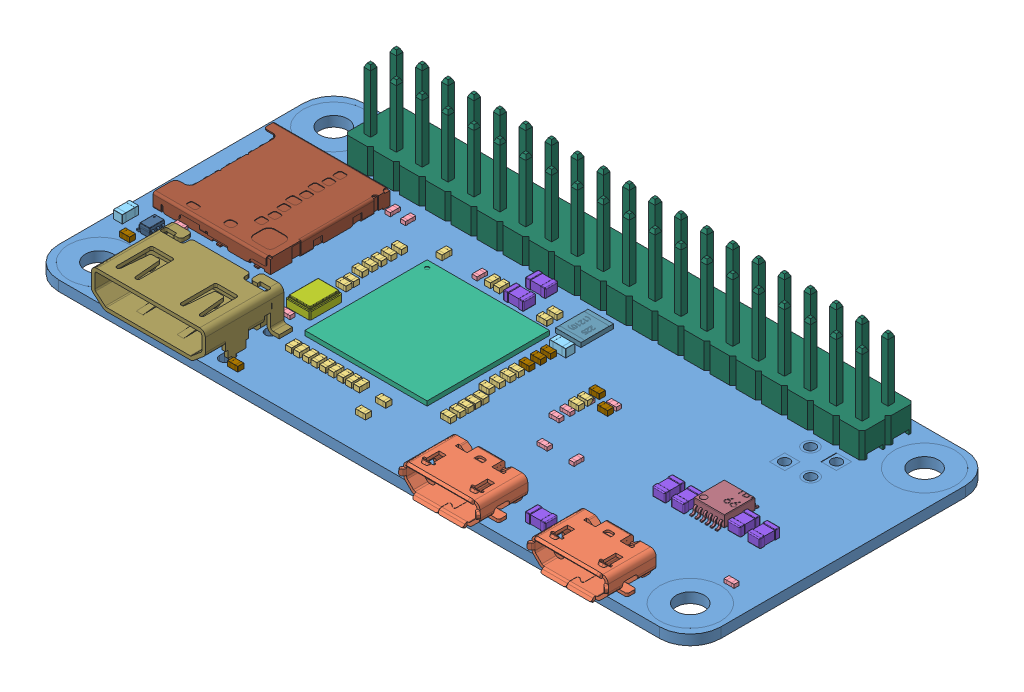
SolidWorks assembly RapberryPiZero, configuration Default. Lengths in mm.
Overall size (65 11.6 31.23).
74 component instances, 15 part files, 139 mates.
Components (placement in the parent):
- Raspberry_pizero_PCB-1: Raspberry_pizero_PCB [Default] at (-51.2564 20.0966 13.0542) size (65 1 30)
- Micro USB_input_female (short)-SMT-1: Micro USB_input_female (short)-SMT [Default] at (-42.3564 22.3216 26.5042) size (7.98 2.94 5.43)
- Micro USB_input_female (short)-SMT-2: Micro USB_input_female (short)-SMT [Default] at (-29.7564 22.3216 26.5042) size (7.98 2.94 5.43)
- 0204 - Capacitor-1: 0204 - Capacitor [Default] at (-66.1059 21.3466 14.3973) size (1 0.5 0.6)
- 0204 - Capacitor-2: 0204 - Capacitor [Default] at (-66.1059 21.3466 13.6661) size (1 0.5 0.6)
- 0204 - Capacitor-3: 0204 - Capacitor [Default] at (-66.4957 21.3466 8.5689) size (1 0.5 0.6)
- 0204 - Capacitor-4: 0204 - Capacitor [Default] at (-66.4957 21.3466 9.5922) size (1 0.5 0.6)
- 0204 - Capacitor-5: 0204 - Capacitor [Default] at (-66.4957 21.3466 10.5547) size (1 0.5 0.6)
- 0204 - Capacitor-6: 0204 - Capacitor [Default] at (-66.4957 21.3466 11.4563) size (1 0.5 0.6)
- 0204 - Capacitor-7: 0204 - Capacitor [Default] at (-66.4957 21.3466 12.4125) size (1 0.5 0.6)
- 0204 - Capacitor-8: 0204 - Capacitor [Default] at (-54.2619 21.3466 22.342) size (1 0.5 0.6)
- 0204 - Capacitor-9: 0204 - Capacitor [Default] at (-54.2619 21.3466 24.3333) size (1 0.5 0.6)
- 0204 - Capacitor-10: 0204 - Capacitor [Default] at (-63.0188 21.3466 22.4185) x (0 0 1) z (-1 0 0) size (1 0.5 0.6)
- 0204 - Capacitor-11: 0204 - Capacitor [Default] at (-62.8505 21.3466 22.4185) x (0 0 -1) z (1 0 0) size (1 0.5 0.6)
- 0204 - Capacitor-12: 0204 - Capacitor [Default] at (-61.9536 21.3466 22.4185) x (0 0 -1) z (1 0 0) size (1 0.5 0.6)
- 0204 - Capacitor-13: 0204 - Capacitor [Default] at (-60.535 21.3466 22.4217) x (0 0 1) z (-1 0 0) size (1 0.5 0.6)
- 0204 - Capacitor-14: 0204 - Capacitor [Default] at (-60.2749 21.3466 22.4217) x (0 0 -1) z (1 0 0) size (1 0.5 0.6)
- 0204 - Capacitor-15: 0204 - Capacitor [Default] at (-59.4762 21.3466 22.4217) x (0 0 -1) z (1 0 0) size (1 0.5 0.6)
- 0204 - Capacitor-16: 0204 - Capacitor [Default] at (-58.5578 21.3466 22.4217) x (0 0 -1) z (1 0 0) size (1 0.5 0.6)
- 0204 - Capacitor-17: 0204 - Capacitor [Default] at (-57.7282 21.3466 22.4217) x (0 0 -1) z (1 0 0) size (1 0.5 0.6)
- 0204 - Capacitor-18: 0204 - Capacitor [Default] at (-49.7633 21.3466 17.2973) size (1 0.5 0.6)
- 0204 - Capacitor-19: 0204 - Capacitor [Default] at (-49.7656 21.3466 20.4911) size (1 0.5 0.6)
- 0204 - Capacitor-20: 0204 - Capacitor [Default] at (-49.7656 21.3466 19.5641) size (1 0.5 0.6)
- 0204 - Capacitor-21: 0204 - Capacitor [Default] at (-49.7656 21.3466 18.764) size (1 0.5 0.6)
- 0204 - Capacitor-22: 0204 - Capacitor [Default] at (-49.7656 21.3466 18.0575) size (1 0.5 0.6)
- 0204 - Capacitor-23: 0204 - Capacitor [Default] at (-50.3207 21.3466 16.1412) size (1 0.5 0.6)
- 0204 - Capacitor-24: 0204 - Capacitor [Default] at (-50.3207 21.3466 15.1225) size (1 0.5 0.6)
- 0204 - Capacitor-25: 0204 - Capacitor [Default] at (-50.3207 21.3466 14.0903) size (1 0.5 0.6)
- 0204 - Capacitor-26: 0204 - Capacitor [Default] at (-50.3207 21.3466 13.2438) size (1 0.5 0.6)
- 0204 - Capacitor-27: 0204 - Capacitor [Default] at (-44.527 21.3466 13.1418) size (1 0.5 0.6)
- 0204 - Capacitor-28: 0204 - Capacitor [Default] at (-44.527 21.3466 12.278) size (1 0.5 0.6)
- 0204 - Capacitor-29: 0204 - Capacitor [Default] at (-53.3159 21.3466 7.4799) size (1 0.5 0.6)
- 0204 - Capacitor-30: 0204 - Capacitor [Default] at (-59.3985 21.3466 7.1313) x (0 0 -1) z (1 0 0) size (1 0.5 0.6)
- 0204 - Capacitor-31: 0204 - Capacitor [Default] at (-57.9118 21.3466 7.1313) x (0 0 1) z (-1 0 0) size (1 0.5 0.6)
- 0204 - Capacitor-32: 0204 - Capacitor [Default] at (-63.5406 21.3466 7.1313) x (0 0 1) z (-1 0 0) size (1 0.5 0.6)
- 0204- Resistor-15: 0204- Resistor [Default] at (-44.5223 21.4522 15.4193) x (-1 0 0) z (0 -1 0) size (0.99 0.51 0.36)
- 0204- Resistor-14: 0204- Resistor [Default] at (-44.5223 21.4522 14.3417) x (-1 0 0) z (0 -1 0) size (0.99 0.51 0.36)
- 0204- Resistor-13: 0204- Resistor [Default] at (-44.5223 21.4522 12.4047) x (-1 0 0) z (0 -1 0) size (0.99 0.51 0.36)
- 0204- Resistor-4: 0204- Resistor [Default] at (-42.6936 21.4522 18.4076) x (-1 0 0) z (0 -1 0) size (0.99 0.51 0.36)
- 0204- Resistor-5: 0204- Resistor [Default] at (-39.831 21.4522 18.1462) x (0 0 1) z (0 -1 0) size (0.99 0.51 0.36)
- 0204- Resistor-7: 0204- Resistor [Default] at (-66.5004 21.4522 19.8533) x (-1 0 0) z (0 -1 0) size (0.99 0.51 0.36)
- 0204- Resistor-9: 0204- Resistor [Default] at (-79.148 21.4522 17.7279) x (-1 0 0) z (0 -1 0) size (0.99 0.51 0.36)
- 0204- Resistor-10: 0204- Resistor [Default] at (-60.3595 21.4522 7.1266) x (0 0 -1) z (0 -1 0) size (0.99 0.51 0.36)
- 0204- Resistor-11: 0204- Resistor [Default] at (-42.6893 21.4522 11.6167) x (-1 0 0) z (0 -1 0) size (0.99 0.51 0.36)
- 0204- Resistor-12: 0204- Resistor [Default] at (-21.8613 21.4522 20.9026) x (-1 0 0) z (0 -1 0) size (0.99 0.51 0.36)
- CAP-0306-1: CAP-0306 [Default] at (-50.0081 21.4966 8.9291) size (1.6 0.8 0.9)
- CAP-0306-2: CAP-0306 [Default] at (-82.3562 21.4966 19.4035) x (0 0 1) z (-1 0 0) size (1.6 0.8 0.9)
- Raspberry_pizero_BCM2835 with VC4-2: Raspberry_pizero_BCM2835 with VC4 [Default] at (-57.9267 21.5466 14.7194) x (1 0 0) z (0 0 -1) size (12 0.65 12)
- Crystal 3.4x2.4mm-1: Crystal 3.4x2.4mm [Default] at (-66.1441 21.0966 17.5946) x (0 0 1) z (-1 0 0) size (3.2 1 2.4)
- 0204- Resistor-16: 0204- Resistor [Default] at (-68.5745 21.4522 5.9384) x (0 0 1) z (0 -1 0) size (0.99 0.51 0.36)
- 0204- Resistor-17: 0204- Resistor [Default] at (-70.0781 21.4522 5.9384) x (0 0 1) z (0 -1 0) size (0.99 0.51 0.36)
- 0805- Capacitor-1: 0805- Capacitor [Default] at (-56.2106 21.9966 5.1919) x (1 0 0) z (0 -1 0) size (2 1.25 0.9)
- 0805- Capacitor-2: 0805- Capacitor [Default] at (-56.2106 21.9966 7.3589) x (1 0 0) z (0 -1 0) size (2 1.25 0.9)
- 0805- Capacitor-3: 0805- Capacitor [Default] at (-36.3007 21.9966 25.1368) x (1 0 0) z (0 -1 0) size (2 1.25 0.9)
- 0805- Capacitor-4: 0805- Capacitor [Default] at (-32.5762 21.9966 16.3326) x (0 0 1) z (0 -1 0) size (2 1.25 0.9)
- 0805- Capacitor-5: 0805- Capacitor [Default] at (-30.7451 21.9966 16.3326) x (0 0 -1) z (0 -1 0) size (2 1.25 0.9)
- 0805- Capacitor-6: 0805- Capacitor [Default] at (-26.001 21.9966 15.5523) x (0 0 -1) z (0 -1 0) size (2 1.25 0.9)
- 0805- Capacitor-7: 0805- Capacitor [Default] at (-24.0466 21.9966 15.5523) x (0 0 -1) z (0 -1 0) size (2 1.25 0.9)
- 0204 - Capacitor-33: 0204 - Capacitor [Default] at (-56.3601 21.3466 22.4168) x (0 0 1) z (-1 0 0) size (1 0.5 0.6)
- 0204 - Capacitor Brown-35: 0204 - Capacitor Brown [Default] at (-64.6013 21.3466 26.5277) size (1 0.5 0.6)
- 0204 - Capacitor Brown-36: 0204 - Capacitor Brown [Default] at (-50.3207 21.3466 12.214) size (1 0.5 0.6)
- 0204 - Capacitor Brown-37: 0204 - Capacitor Brown [Default] at (-50.3207 21.3466 11.0963) size (1 0.5 0.6)
- 0204 - Capacitor Brown-38: 0204 - Capacitor Brown [Default] at (-50.3207 21.3466 10.1084) size (1 0.5 0.6)
- 0204 - Capacitor Brown-39: 0204 - Capacitor Brown [Default] at (-44.527 21.3466 11.1151) size (1 0.5 0.6)
- 0204 - Capacitor Brown-40: 0204 - Capacitor Brown [Default] at (-42.694 21.3466 12.1364) size (1 0.5 0.6)
- 0204 - Capacitor Brown-41: 0204 - Capacitor Brown [Default] at (-80.9029 21.3466 20.8434) size (1 0.5 0.6)
- 0204- Resistor-21: 0204- Resistor [Default] at (-79.0538 21.4522 20.9432) x (1 0 0) z (0 -1 0) size (0.99 0.51 0.36)
- 6-Pin SOT-1: 6-Pin SOT [Default] at (-80.2098 21.0966 19.4296) x (0 0 1) z (0 1 0) size (1.5 1.84 0.95)
- micro sd molex-1: micro sd molex [Default] at (-74.7768 21.6766 -33.0961) x (0 0 1) z (0 1 0) size (11.95 11.4 1.45)
- hdmi type C-1: hdmi type C [Default] at (-71.3564 22.9466 28.6542) size (12.9 4.05 7.7)
- Voltage Regulator 3x3mm 12-Pin-1: Voltage Regulator 3x3mm 12-Pin [Default] at (-26.5859 21.0966 14.3315) x (1 0 0) z (0 1 0) size (3 4.1 1.2)
- 1210 inductor-1: 1210 inductor [Default] at (-50.6117 20.9774 6.5916) x (0 0 1) z (0 1 0) size (3.26 2.86 0.75)
- 0204 - Capacitor-34: 0204 - Capacitor [Default] at (-53.3159 21.3466 6.4804) size (1 0.5 0.6)
- raspberry_pi_B+_(bar_180_2x20)-1: raspberry_pi_B+_(bar_180_2x20) [Default] at (-75.3864 23.5966 0.2742) x (0 0 -1) z (-1 0 0) size (5.08 11.6 50.8)
Mates (geometry in assembly coordinates):
- Coincident1: coincident anti-aligned: plane of Raspberry_pizero_PCB-1 through (-80.7564 21.0966 1.0542) normal (0 1 0); plane of Micro USB_input_female (short)-SMT-1 through (-46.4124 21.0966 24.8966) normal (0 -1 0)
- Coincident2: coincident anti-aligned: plane of Raspberry_pizero_PCB-1 through (-80.7564 21.0966 1.0542) normal (0 1 0); plane of Micro USB_input_female (short)-SMT-2 through (-33.8124 21.0966 24.8966) normal (0 -1 0)
- Coincident3: coincident aligned: plane of 0204 - Capacitor-13 through (-60.837 21.5916 22.4217) normal (0 1 0); plane of 0204 - Capacitor-14 through (-59.9729 21.5916 22.4217) normal (0 1 0)
- Coincident4: coincident aligned: plane of 0204 - Capacitor-14 through (-59.9729 21.5916 22.4217) normal (0 1 0); plane of 0204 - Capacitor-15 through (-59.1742 21.5916 22.4217) normal (0 1 0)
- Coincident5: coincident aligned: plane of 0204 - Capacitor-15 through (-59.1742 21.5916 22.4217) normal (0 1 0); plane of 0204 - Capacitor-16 through (-58.2558 21.5916 22.4217) normal (0 1 0)
- Coincident6: coincident aligned: plane of 0204 - Capacitor-16 through (-58.2558 21.5916 22.4217) normal (0 1 0); plane of 0204 - Capacitor-17 through (-57.4262 21.5916 22.4217) normal (0 1 0)
- Coincident7: coincident aligned: plane of 0204 - Capacitor-17 through (-57.4262 21.5916 22.4217) normal (0 1 0); plane of 0204 - Capacitor-18 through (-49.7633 21.5916 17.5993) normal (0 1 0)
- Coincident8: coincident aligned: plane of 0204 - Capacitor-18 through (-49.7633 21.5916 17.5993) normal (0 1 0); plane of 0204 - Capacitor-19 through (-49.7656 21.5916 20.7931) normal (0 1 0)
- Coincident9: coincident aligned: plane of 0204 - Capacitor-19 through (-49.7656 21.5916 20.7931) normal (0 1 0); plane of 0204 - Capacitor-20 through (-49.7656 21.5916 19.8661) normal (0 1 0)
- Coincident10: coincident aligned: plane of 0204 - Capacitor-20 through (-49.7656 21.5916 19.8661) normal (0 1 0); plane of 0204 - Capacitor-21 through (-49.7656 21.5916 19.066) normal (0 1 0)
- Coincident11: coincident aligned: plane of 0204 - Capacitor-21 through (-49.7656 21.5916 19.066) normal (0 1 0); plane of 0204 - Capacitor-22 through (-49.7656 21.5916 18.3595) normal (0 1 0)
- Coincident12: coincident aligned: plane of 0204 - Capacitor-22 through (-49.7656 21.5916 18.3595) normal (0 1 0); plane of 0204 - Capacitor-23 through (-50.3207 21.5916 16.4432) normal (0 1 0)
- Coincident13: coincident aligned: plane of 0204 - Capacitor-23 through (-50.3207 21.5916 16.4432) normal (0 1 0); plane of 0204 - Capacitor-24 through (-50.3207 21.5916 15.4245) normal (0 1 0)
- Coincident14: coincident aligned: plane of 0204 - Capacitor-24 through (-50.3207 21.5916 15.4245) normal (0 1 0); plane of 0204 - Capacitor-25 through (-50.3207 21.5916 14.3923) normal (0 1 0)
- Coincident15: coincident aligned: plane of 0204 - Capacitor-25 through (-50.3207 21.5916 14.3923) normal (0 1 0); plane of 0204 - Capacitor-26 through (-50.3207 21.5916 13.5458) normal (0 1 0)
- Coincident16: coincident aligned: plane of 0204 - Capacitor-26 through (-50.3207 21.5916 13.5458) normal (0 1 0); plane of 0204 - Capacitor-27 through (-44.527 21.5916 13.4438) normal (0 1 0)
- Coincident17: coincident aligned: plane of 0204 - Capacitor-27 through (-44.527 21.5916 13.4438) normal (0 1 0); plane of 0204 - Capacitor-28 through (-44.527 21.5916 12.58) normal (0 1 0)
- Coincident18: coincident aligned: plane of 0204 - Capacitor-28 through (-44.527 21.5916 12.58) normal (0 1 0); plane of 0204 - Capacitor-29 through (-53.3159 21.5916 7.7819) normal (0 1 0)
- Coincident19: coincident aligned: plane of 0204 - Capacitor-29 through (-53.3159 21.5916 7.7819) normal (0 1 0); plane of 0204 - Capacitor-31 through (-58.2138 21.5916 7.1313) normal (0 1 0)
- Coincident20: coincident aligned: plane of 0204 - Capacitor-30 through (-59.0965 21.5916 7.1313) normal (0 1 0); plane of 0204 - Capacitor-31 through (-58.2138 21.5916 7.1313) normal (0 1 0)
- Coincident21: coincident aligned: plane of 0204 - Capacitor-30 through (-59.0965 21.5916 7.1313) normal (0 1 0); plane of 0204 - Capacitor-32 through (-63.8426 21.5916 7.1313) normal (0 1 0)
- Coincident22: coincident aligned: plane of 0204 - Capacitor-1 through (-66.1059 21.5916 14.6993) normal (0 1 0); plane of 0204 - Capacitor-32 through (-63.8426 21.5916 7.1313) normal (0 1 0)
- Coincident23: coincident aligned: plane of 0204 - Capacitor-1 through (-66.1059 21.5916 14.6993) normal (0 1 0); plane of 0204 - Capacitor-2 through (-66.1059 21.5916 13.9681) normal (0 1 0)
- Coincident24: coincident aligned: plane of 0204 - Capacitor-2 through (-66.1059 21.5916 13.9681) normal (0 1 0); plane of 0204 - Capacitor-3 through (-66.4957 21.5916 8.8709) normal (0 1 0)
- Coincident25: coincident aligned: plane of 0204 - Capacitor-3 through (-66.4957 21.5916 8.8709) normal (0 1 0); plane of 0204 - Capacitor-4 through (-66.4957 21.5916 9.8942) normal (0 1 0)
- Coincident26: coincident aligned: plane of 0204 - Capacitor-4 through (-66.4957 21.5916 9.8942) normal (0 1 0); plane of 0204 - Capacitor-5 through (-66.4957 21.5916 10.8567) normal (0 1 0)
- Coincident27: coincident aligned: plane of 0204 - Capacitor-5 through (-66.4957 21.5916 10.8567) normal (0 1 0); plane of 0204 - Capacitor-6 through (-66.4957 21.5916 11.7583) normal (0 1 0)
- Coincident28: coincident aligned: plane of 0204 - Capacitor-6 through (-66.4957 21.5916 11.7583) normal (0 1 0); plane of 0204 - Capacitor-7 through (-66.4957 21.5916 12.7145) normal (0 1 0)
- Coincident29: coincident aligned: plane of 0204 - Capacitor-7 through (-66.4957 21.5916 12.7145) normal (0 1 0); plane of 0204 - Capacitor-8 through (-54.2619 21.5916 22.644) normal (0 1 0)
- Coincident31: coincident aligned: plane of 0204 - Capacitor-9 through (-54.2619 21.5916 24.6353) normal (0 1 0); plane of 0204 - Capacitor-10 through (-63.3208 21.5916 22.4185) normal (0 1 0)
- Coincident30: coincident aligned: plane of 0204 - Capacitor-8 through (-54.2619 21.5916 22.644) normal (0 1 0); plane of 0204 - Capacitor-9 through (-54.2619 21.5916 24.6353) normal (0 1 0)
- Coincident32: coincident aligned: plane of 0204 - Capacitor-10 through (-63.3208 21.5916 22.4185) normal (0 1 0); plane of 0204 - Capacitor-11 through (-62.5485 21.5916 22.4185) normal (0 1 0)
- Coincident33: coincident aligned: plane of 0204 - Capacitor-11 through (-62.5485 21.5916 22.4185) normal (0 1 0); plane of 0204 - Capacitor-12 through (-61.6516 21.5916 22.4185) normal (0 1 0)
- Coincident34: coincident anti-aligned: plane of Raspberry_pizero_PCB-1 through (-80.7564 21.0966 1.0542) normal (0 1 0); plane of 0204 - Capacitor-9 through (-54.6369 21.0966 24.6333) normal (0 -1 0)
- Coincident35: coincident aligned: plane of 0204 - Capacitor-25 through (-50.8207 21.0966 14.3903) normal (-1 0 0); plane of 0204 - Capacitor-26 through (-50.8207 21.0966 13.5438) normal (-1 0 0)
- Coincident36: coincident aligned: plane of 0204 - Capacitor-24 through (-50.8207 21.0966 15.4225) normal (-1 0 0); plane of 0204 - Capacitor-25 through (-50.8207 21.0966 14.3903) normal (-1 0 0)
- Coincident37: coincident aligned: plane of 0204 - Capacitor-23 through (-50.8207 21.0966 16.4412) normal (-1 0 0); plane of 0204 - Capacitor-24 through (-50.8207 21.0966 15.4225) normal (-1 0 0)
- Coincident38: coincident aligned: plane of 0204 - Capacitor-27 through (-45.027 21.0966 13.4418) normal (-1 0 0); plane of 0204 - Capacitor-28 through (-45.027 21.0966 12.578) normal (-1 0 0)
- Parallel1: parallel anti-aligned: plane of Raspberry_pizero_PCB-1 through (-80.7564 21.0966 -1.9458) normal (0 0 -1); plane of 0204 - Capacitor-30 through (-59.0985 21.0966 7.6313) normal (0 0 1)
- Coincident39: coincident aligned: plane of 0204 - Capacitor-30 through (-59.0985 21.0966 6.6313) normal (0 0 -1); plane of 0204 - Capacitor-31 through (-58.2118 21.0966 6.6313) normal (0 0 -1)
- Coincident40: coincident aligned: plane of 0204 - Capacitor-30 through (-59.0985 21.0966 6.6313) normal (0 0 -1); plane of 0204 - Capacitor-32 through (-63.8406 21.0966 6.6313) normal (0 0 -1)
- Coincident41: coincident aligned: plane of 0204 - Capacitor-1 through (-66.6059 21.0966 14.6973) normal (-1 0 0); plane of 0204 - Capacitor-2 through (-66.6059 21.0966 13.9661) normal (-1 0 0)
- Coincident42: coincident aligned: plane of 0204 - Capacitor-3 through (-66.9957 21.0966 8.8689) normal (-1 0 0); plane of 0204 - Capacitor-4 through (-66.9957 21.0966 9.8922) normal (-1 0 0)
- Coincident43: coincident aligned: plane of 0204 - Capacitor-4 through (-66.9957 21.0966 9.8922) normal (-1 0 0); plane of 0204 - Capacitor-5 through (-66.9957 21.0966 10.8547) normal (-1 0 0)
- Coincident44: coincident aligned: plane of 0204 - Capacitor-5 through (-66.9957 21.0966 10.8547) normal (-1 0 0); plane of 0204 - Capacitor-6 through (-66.9957 21.0966 11.7563) normal (-1 0 0)
- Coincident45: coincident aligned: plane of 0204 - Capacitor-6 through (-66.9957 21.0966 11.7563) normal (-1 0 0); plane of 0204 - Capacitor-7 through (-66.9957 21.0966 12.7125) normal (-1 0 0)
- Coincident46: coincident aligned: plane of 0204 - Capacitor-8 through (-54.7619 21.0966 22.642) normal (-1 0 0); plane of 0204 - Capacitor-9 through (-54.7619 21.0966 24.6333) normal (-1 0 0)
- Parallel2: parallel anti-aligned: plane of Raspberry_pizero_PCB-1 through (-80.7564 21.0966 28.0542) normal (0 0 1); plane of 0204 - Capacitor-10 through (-63.3188 21.0966 21.9185) normal (0 0 -1)
- Coincident48: coincident aligned: plane of 0204 - Capacitor-10 through (-63.3188 21.0966 22.9185) normal (0 0 1); plane of 0204 - Capacitor-11 through (-62.5505 21.0966 22.9185) normal (0 0 1)
- Coincident49: coincident aligned: plane of 0204 - Capacitor-11 through (-62.5505 21.0966 22.9185) normal (0 0 1); plane of 0204 - Capacitor-12 through (-61.6536 21.0966 22.9185) normal (0 0 1)
- Parallel3: parallel anti-aligned: plane of Raspberry_pizero_PCB-1 through (-80.7564 21.0966 28.0542) normal (0 0 1); plane of 0204 - Capacitor-13 through (-60.835 21.0966 21.9217) normal (0 0 -1)
- Coincident51: coincident aligned: plane of 0204 - Capacitor-13 through (-60.835 21.0966 22.9217) normal (0 0 1); plane of 0204 - Capacitor-14 through (-59.9749 21.0966 22.9217) normal (0 0 1)
- Coincident52: coincident aligned: plane of 0204 - Capacitor-14 through (-59.9749 21.0966 22.9217) normal (0 0 1); plane of 0204 - Capacitor-15 through (-59.1762 21.0966 22.9217) normal (0 0 1)
- Coincident53: coincident aligned: plane of 0204 - Capacitor-15 through (-59.1762 21.0966 22.9217) normal (0 0 1); plane of 0204 - Capacitor-16 through (-58.2578 21.0966 22.9217) normal (0 0 1)
- Coincident54: coincident aligned: plane of 0204 - Capacitor-16 through (-58.2578 21.0966 22.9217) normal (0 0 1); plane of 0204 - Capacitor-17 through (-57.4282 21.0966 22.9217) normal (0 0 1)
- Parallel7: parallel anti-aligned: plane of Raspberry_pizero_PCB-1 through (-80.7564 21.0966 28.0542) normal (0 0 1); plane of CAP-0306-2 through (-82.8062 21.0966 18.6035) normal (0 0 -1)
- Parallel8: parallel aligned: plane of Raspberry_pizero_PCB-1 through (-18.7564 21.0966 25.0542) normal (1 0 0); plane of CAP-0306-1 through (-49.2081 21.0966 9.3791) normal (1 0 0)
- Coincident77: coincident aligned: plane of 0204 - Capacitor-21 through (-50.2656 21.0966 19.064) normal (-1 0 0); plane of 0204 - Capacitor-22 through (-50.2656 21.0966 18.3575) normal (-1 0 0)
- Coincident78: coincident aligned: plane of 0204 - Capacitor-20 through (-50.2656 21.0966 19.8641) normal (-1 0 0); plane of 0204 - Capacitor-21 through (-50.2656 21.0966 19.064) normal (-1 0 0)
- Coincident79: coincident aligned: plane of 0204 - Capacitor-19 through (-50.2656 21.0966 20.7911) normal (-1 0 0); plane of 0204 - Capacitor-20 through (-50.2656 21.0966 19.8641) normal (-1 0 0)
- Coincident80: coincident aligned: plane of Micro USB_input_female (short)-SMT-1 through (-39.2364 21.3596 23.8542) normal (0 0 -1); plane of Micro USB_input_female (short)-SMT-2 through (-26.6364 21.3596 23.8542) normal (0 0 -1)
- Distance1: distance = 41.4 mm: point of Micro USB_input_female (short)-SMT-1; plane of Raspberry_pizero_PCB-1 through (-83.7564 21.0966 25.0542) normal (-1 0 0)
- Distance3: distance = 0.8 mm aligned: plane of Micro USB_input_female (short)-SMT-1 through (-46.2564 21.0476 28.8542) normal (0 0 1); plane of Raspberry_pizero_PCB-1 through (-80.7564 21.0966 28.0542) normal (0 0 1)
- Distance4: distance = 54 mm: unknown of Micro USB_input_female (short)-SMT-2; plane of Raspberry_pizero_PCB-1 through (-83.7564 21.0966 25.0542) normal (-1 0 0)
- Coincident86: coincident anti-aligned: plane of Raspberry_pizero_PCB-1 through (-80.7564 21.0966 1.0542) normal (0 1 0); plane of Raspberry_pizero_BCM2835 with VC4-2 through (-57.9267 21.0966 14.7194) normal (0 -1 0)
- Parallel10: parallel anti-aligned: plane of Raspberry_pizero_BCM2835 with VC4-2 through (-63.9267 21.0966 8.7194) normal (0 0 -1); plane of Raspberry_pizero_PCB-1 through (-80.7564 21.0966 28.0542) normal (0 0 1)
- Coincident88: coincident anti-aligned: plane of Raspberry_pizero_PCB-1 through (-80.7564 21.0966 1.0542) normal (0 1 0); plane of CAP-0306-1 through (-49.3831 21.0966 9.3791) normal (0 -1 0)
- Parallel11: parallel aligned: plane of Raspberry_pizero_PCB-1 through (-80.7564 21.0966 28.0542) normal (0 0 1); plane of 0204 - Capacitor-7 through (-66.4957 21.1016 13.0115) normal (0 0 1)
- Coincident94: coincident aligned: plane of 0204 - Capacitor-30 through (-59.0985 21.0966 6.6313) normal (0 0 -1); plane of 0204- Resistor-10 through (-60.1055 21.0966 6.6313) normal (0 0 -1)
- Coincident95: coincident anti-aligned: plane of Raspberry_pizero_PCB-1 through (-80.7564 21.0966 1.0542) normal (0 1 0); plane of 0204- Resistor-10 through (-60.1055 21.0966 6.8345) normal (0 -1 0)
- Coincident96: coincident aligned: plane of 0204- Resistor-14 through (-44.8144 21.0966 14.0877) normal (0 -1 0); plane of 0204- Resistor-13 through (-44.8144 21.0966 12.1507) normal (0 -1 0)
- Coincident97: coincident aligned: plane of 0204- Resistor-15 through (-44.8144 21.0966 15.1653) normal (0 -1 0); plane of 0204- Resistor-14 through (-44.8144 21.0966 14.0877) normal (0 -1 0)
- Coincident98: coincident aligned: plane of 0204- Resistor-15 through (-44.8144 21.0966 15.1653) normal (0 -1 0); plane of 0204- Resistor-4 through (-42.9857 21.0966 18.1536) normal (0 -1 0)
- Coincident99: coincident anti-aligned: plane of Raspberry_pizero_PCB-1 through (-80.7564 21.0966 1.0542) normal (0 1 0); plane of 0204- Resistor-15 through (-44.8144 21.0966 15.1653) normal (0 -1 0)
- Coincident101: coincident aligned: plane of 0204- Resistor-5 through (-40.085 21.0966 18.4383) normal (0 -1 0); plane of 0204- Resistor-11 through (-42.3972 21.0966 11.3627) normal (0 -1 0)
- Coincident102: coincident aligned: plane of 0204- Resistor-11 through (-42.3972 21.0966 11.3627) normal (0 -1 0); plane of 0204- Resistor-12 through (-21.5692 21.0966 20.6486) normal (0 -1 0)
- Coincident103: coincident anti-aligned: plane of Raspberry_pizero_PCB-1 through (-80.7564 21.0966 1.0542) normal (0 1 0); plane of Crystal 3.4x2.4mm-1 through (-66.1441 21.0966 17.5946) normal (0 -1 0)
- Parallel12: parallel aligned: plane of Crystal 3.4x2.4mm-1 through (-67.3441 21.7966 15.9946) normal (-1 0 0); plane of Raspberry_pizero_BCM2835 with VC4-2 through (-63.9267 21.0966 8.7194) normal (-1 0 0)
- Coincident104: coincident anti-aligned: plane of Raspberry_pizero_PCB-1 through (-80.7564 21.0966 1.0542) normal (0 1 0); plane of 0204- Resistor-9 through (-78.8559 21.0966 17.4739) normal (0 -1 0)
- Parallel13: parallel aligned: plane of Raspberry_pizero_PCB-1 through (-80.7564 21.0966 28.0542) normal (0 0 1); plane of 0204- Resistor-9 through (-78.2985 21.4532 17.9829) normal (0 0 1)
- Coincident105: coincident anti-aligned: plane of Raspberry_pizero_PCB-1 through (-80.7564 21.0966 1.0542) normal (0 1 0); plane of CAP-0306-2 through (-82.8062 21.0966 20.0285) normal (0 -1 0)
- Coincident106: coincident aligned: plane of 0204 - Capacitor-28 through (-44.027 21.0966 12.578) normal (1 0 0); plane of 0204- Resistor-13 through (-44.027 21.0966 12.1507) normal (1 0 0)
- Coincident107: coincident aligned: plane of 0204 - Capacitor-27 through (-44.027 21.0966 13.4418) normal (1 0 0); plane of 0204- Resistor-14 through (-44.027 21.0966 14.0877) normal (1 0 0)
- Parallel14: parallel aligned: plane of Raspberry_pizero_PCB-1 through (-80.7564 21.0966 28.0542) normal (0 0 1); plane of 0204- Resistor-14 through (-43.6728 21.4532 14.5967) normal (0 0 1)
- Coincident110: coincident aligned: plane of 0204- Resistor-15 through (-44.027 21.0966 15.1653) normal (1 0 0); plane of 0204- Resistor-14 through (-44.027 21.0966 14.0877) normal (1 0 0)
- Parallel15: parallel aligned: plane of 0204- Resistor-15 through (-44.027 21.0966 15.1653) normal (1 0 0); plane of 0204- Resistor-4 through (-42.1983 21.0966 18.1536) normal (1 0 0)
- Parallel16: parallel aligned: plane of Raspberry_pizero_PCB-1 through (-80.7564 21.0966 28.0542) normal (0 0 1); plane of 0204- Resistor-5 through (-40.085 21.0966 18.6415) normal (0 0 1)
- Coincident112: coincident anti-aligned: plane of Raspberry_pizero_PCB-1 through (-80.7564 21.0966 1.0542) normal (0 1 0); plane of 0204- Resistor-5 through (-40.085 21.0966 18.4383) normal (0 -1 0)
- Parallel17: parallel aligned: plane of Raspberry_pizero_PCB-1 through (-18.7564 21.0966 25.0542) normal (1 0 0); plane of 0204- Resistor-12 through (-21.366 21.0966 20.6486) normal (1 0 0)
- Parallel18: parallel aligned: plane of 0204- Resistor-11 through (-42.194 21.0966 11.3627) normal (1 0 0); plane of 0204- Resistor-12 through (-21.366 21.0966 20.6486) normal (1 0 0)
- Coincident115: coincident anti-aligned: plane of Raspberry_pizero_PCB-1 through (-80.7564 21.0966 1.0542) normal (0 1 0); plane of 0204- Resistor-16 through (-68.8285 21.0966 5.6463) normal (0 -1 0)
- Coincident116: coincident aligned: plane of 0204- Resistor-16 through (-68.8295 21.4532 5.0889) normal (0 1 0); plane of 0204- Resistor-17 through (-70.3331 21.4532 5.0889) normal (0 1 0)
- Coincident118: coincident aligned: plane of 0204- Resistor-16 through (-68.8285 21.0966 6.4337) normal (0 0 1); plane of 0204- Resistor-17 through (-70.3321 21.0966 6.4337) normal (0 0 1)
- Parallel19: parallel anti-aligned: plane of Raspberry_pizero_PCB-1 through (-80.7564 21.0966 -1.9458) normal (0 0 -1); plane of 0204- Resistor-17 through (-70.3321 21.0966 6.4337) normal (0 0 1)
- Coincident121: coincident anti-aligned: plane of Raspberry_pizero_PCB-1 through (-80.7564 21.0966 1.0542) normal (0 1 0); plane of 0805- Capacitor-1 through (-57.2106 21.0966 5.8169) normal (0 -1 0)
- Coincident122: coincident anti-aligned: plane of Raspberry_pizero_PCB-1 through (-80.7564 21.0966 1.0542) normal (0 1 0); plane of 0805- Capacitor-2 through (-57.2106 21.0966 7.9839) normal (0 -1 0)
- Coincident123: coincident anti-aligned: plane of Raspberry_pizero_PCB-1 through (-80.7564 21.0966 1.0542) normal (0 1 0); plane of 0805- Capacitor-3 through (-35.3007 21.0966 24.5118) normal (0 -1 0)
- Coincident124: coincident anti-aligned: plane of Raspberry_pizero_PCB-1 through (-80.7564 21.0966 1.0542) normal (0 1 0); plane of 0805- Capacitor-4 through (-33.2012 21.0966 15.3326) normal (0 -1 0)
- Coincident125: coincident anti-aligned: plane of Raspberry_pizero_PCB-1 through (-80.7564 21.0966 1.0542) normal (0 1 0); plane of 0805- Capacitor-5 through (-30.1201 21.0966 17.3326) normal (0 -1 0)
- Parallel21: parallel anti-aligned: plane of Raspberry_pizero_PCB-1 through (-80.7564 21.0966 28.0542) normal (0 0 1); plane of 0805- Capacitor-4 through (-32.5762 21.9966 15.3326) normal (0 0 -1)
- Coincident126: coincident aligned: plane of 0805- Capacitor-4 through (-32.5762 21.9966 17.3326) normal (0 0 1); plane of 0805- Capacitor-5 through (-30.7451 21.9966 17.3326) normal (0 0 1)
- Coincident127: coincident anti-aligned: plane of Raspberry_pizero_PCB-1 through (-80.7564 21.0966 1.0542) normal (0 1 0); plane of 0805- Capacitor-6 through (-25.376 21.0966 16.5523) normal (0 -1 0)
- Coincident128: coincident anti-aligned: plane of Raspberry_pizero_PCB-1 through (-80.7564 21.0966 1.0542) normal (0 1 0); plane of 0805- Capacitor-7 through (-23.4216 21.0966 16.5523) normal (0 -1 0)
- Coincident130: coincident aligned: plane of 0805- Capacitor-6 through (-26.001 21.9966 16.5523) normal (0 0 1); plane of 0805- Capacitor-7 through (-24.0466 21.9966 16.5523) normal (0 0 1)
- Parallel22: parallel aligned: plane of Raspberry_pizero_PCB-1 through (-80.7564 21.0966 28.0542) normal (0 0 1); plane of 0805- Capacitor-3 through (-37.3007 21.9966 25.7618) normal (0 0 1)
- Coincident131: coincident aligned: plane of 0805- Capacitor-1 through (-55.2106 21.9966 5.1919) normal (1 0 0); plane of 0805- Capacitor-2 through (-55.2106 21.9966 7.3589) normal (1 0 0)
- Parallel23: parallel anti-aligned: plane of Raspberry_pizero_PCB-1 through (-80.7564 21.0966 28.0542) normal (0 0 1); plane of 6-Pin SOT-1 through (-80.7098 22.0466 18.6796) normal (0 0 -1)
- Coincident134: coincident anti-aligned: plane of Raspberry_pizero_PCB-1 through (-80.7564 21.0966 1.0542) normal (0 1 0); plane of 6-Pin SOT-1 through (-80.9298 21.0966 20.0421) normal (0 -1 0)
- Coincident135: coincident anti-aligned: plane of Raspberry_pizero_PCB-1 through (-80.7564 21.0966 1.0542) normal (0 1 0); plane of micro sd molex-1 through (-71.1444 21.0966 16.7043) normal (0 -1 0)
- Parallel24: parallel aligned: plane of Raspberry_pizero_PCB-1 through (-80.7564 21.0966 -1.9458) normal (0 0 -1); plane of micro sd molex-1 through (-84.5393 22.448 5.3989) normal (0 0 -1)
- Coincident141: coincident anti-aligned: plane of Raspberry_pizero_PCB-1 through (-80.7564 21.0966 1.0542) normal (0 1 0); plane of hdmi type C-1 through (-77.8064 21.0966 20.9542) normal (0 -1 0)
- Distance5: distance = 12.4 mm: unknown of hdmi type C-1; plane of Raspberry_pizero_PCB-1 through (-83.7564 21.0966 25.0542) normal (-1 0 0)
- Distance6: distance = 17.2 mm: unknown of micro sd molex-1; plane of Raspberry_pizero_PCB-1 through (-80.7564 21.0966 28.0542) normal (0 0 1)
- Parallel25: parallel aligned: plane of Raspberry_pizero_PCB-1 through (-80.7564 21.0966 28.0542) normal (0 0 1); plane of hdmi type C-1 through (-71.3564 22.9466 28.6542) normal (0 0 1)
- Distance7: distance = 0.6 mm aligned: plane of hdmi type C-1 through (-71.3564 22.9466 28.6542) normal (0 0 1); plane of Raspberry_pizero_PCB-1 through (-80.7564 21.0966 28.0542) normal (0 0 1)
- Coincident144: coincident aligned: plane of 0204 - Capacitor-18 through (-49.7633 21.5916 17.5993) normal (0 1 0); plane of 0204 - Capacitor-33 through (-56.6621 21.5916 22.4168) normal (0 1 0)
- Parallel26: parallel anti-aligned: plane of Raspberry_pizero_PCB-1 through (-80.7564 21.0966 28.0542) normal (0 0 1); plane of 0204 - Capacitor-33 through (-56.6601 21.0966 21.9168) normal (0 0 -1)
- Coincident148: coincident anti-aligned: plane of Raspberry_pizero_PCB-1 through (-80.7564 21.0966 1.0542) normal (0 1 0); plane of 0204- Resistor-21 through (-79.3459 21.0966 21.1972) normal (0 -1 0)
- Coincident149: coincident anti-aligned: plane of Raspberry_pizero_PCB-1 through (-80.7564 21.0966 1.0542) normal (0 1 0); plane of 0204 - Capacitor Brown-41 through (-81.2779 21.0966 21.1434) normal (0 -1 0)
- Parallel27: parallel aligned: plane of Raspberry_pizero_PCB-1 through (-80.7564 21.0966 28.0542) normal (0 0 1); plane of 0204- Resistor-21 through (-79.0538 21.4522 21.1972) normal (0 0 1)
- Parallel28: parallel aligned: plane of Raspberry_pizero_PCB-1 through (-80.7564 21.0966 28.0542) normal (0 0 1); plane of 0204 - Capacitor Brown-41 through (-80.9029 21.1016 21.4424) normal (0 0 1)
- Coincident153: coincident aligned: plane of 0204 - Capacitor Brown-36 through (-50.3207 21.5916 12.516) normal (0 1 0); plane of 0204 - Capacitor Brown-39 through (-44.527 21.5916 11.4171) normal (0 1 0)
- Coincident154: coincident aligned: plane of 0204 - Capacitor Brown-36 through (-50.3207 21.5916 12.516) normal (0 1 0); plane of 0204 - Capacitor Brown-37 through (-50.3207 21.5916 11.3983) normal (0 1 0)
- Coincident155: coincident aligned: plane of 0204 - Capacitor Brown-37 through (-50.3207 21.5916 11.3983) normal (0 1 0); plane of 0204 - Capacitor Brown-38 through (-50.3207 21.5916 10.4104) normal (0 1 0)
- Coincident156: coincident aligned: plane of 0204 - Capacitor-26 through (-49.8207 21.0966 13.5438) normal (1 0 0); plane of 0204 - Capacitor Brown-36 through (-49.8207 21.0966 12.514) normal (1 0 0)
- Coincident157: coincident aligned: plane of 0204 - Capacitor Brown-36 through (-49.8207 21.0966 12.514) normal (1 0 0); plane of 0204 - Capacitor Brown-37 through (-49.8207 21.0966 11.3963) normal (1 0 0)
- Coincident158: coincident aligned: plane of 0204 - Capacitor Brown-37 through (-49.8207 21.0966 11.3963) normal (1 0 0); plane of 0204 - Capacitor Brown-38 through (-49.8207 21.0966 10.4084) normal (1 0 0)
- Coincident159: coincident aligned: plane of 0204 - Capacitor-28 through (-44.027 21.0966 12.578) normal (1 0 0); plane of 0204 - Capacitor Brown-39 through (-44.027 21.0966 11.4151) normal (1 0 0)
- Coincident160: coincident aligned: plane of 0204 - Capacitor Brown-39 through (-44.527 21.5916 11.4171) normal (0 1 0); plane of 0204 - Capacitor Brown-40 through (-42.694 21.5916 12.4384) normal (0 1 0)
- Coincident161: coincident aligned: plane of 0204- Resistor-11 through (-42.194 21.0966 11.3627) normal (1 0 0); plane of 0204 - Capacitor Brown-40 through (-42.194 21.0966 12.4364) normal (1 0 0)
- Coincident163: coincident anti-aligned: plane of Raspberry_pizero_PCB-1 through (-80.7564 21.0966 1.0542) normal (0 1 0); plane of Voltage Regulator 3x3mm 12-Pin-1 through (-27.0359 21.0966 13.0327) normal (0 -1 0)
- Parallel30: parallel aligned: plane of Raspberry_pizero_PCB-1 through (-18.7564 21.0966 25.0542) normal (1 0 0); plane of Voltage Regulator 3x3mm 12-Pin-1 through (-26.8859 22.2966 13.5815) normal (1 0 0)
- Coincident167: coincident aligned: plane of 0204 - Capacitor-29 through (-53.3159 21.5916 7.7819) normal (0 1 0); plane of 0204 - Capacitor-34 through (-53.3159 21.5916 6.7824) normal (0 1 0)
- Coincident168: coincident aligned: plane of 0204 - Capacitor-29 through (-53.8159 21.0966 7.7799) normal (-1 0 0); plane of 0204 - Capacitor-34 through (-53.8159 21.0966 6.7804) normal (-1 0 0)
- Parallel33: parallel aligned: plane of Raspberry_pizero_PCB-1 through (-18.7564 21.0966 25.0542) normal (1 0 0); plane of 1210 inductor-1 through (-49.3622 21.2524 6.5916) normal (1 0 0)
- Coïncidente1: coincident anti-aligned: plane of Raspberry_pizero_PCB-1 through (-80.7564 21.0966 1.0542) normal (0 1 0); plane of raspberry_pi_B+_(bar_180_2x20)-1 through (-75.3864 21.0966 2.5142) normal (0 -1 0)
- Parallèle1: parallel aligned: plane of Raspberry_pizero_PCB-1 through (-80.7564 21.0966 -1.9458) normal (0 0 -1); plane of raspberry_pi_B+_(bar_180_2x20)-1 through (-61.7164 21.0966 -0.9958) normal (0 0 -1)
- Distance8: distance = 7.1 mm aligned: plane of raspberry_pi_B+_(bar_180_2x20)-1 through (-76.6564 21.0966 1.8442) normal (-1 0 0); plane of Raspberry_pizero_PCB-1 through (-83.7564 21.0966 25.0542) normal (-1 0 0)
- Distance9: distance = 0.95 mm aligned: plane of Raspberry_pizero_PCB-1 through (-80.7564 21.0966 -1.9458) normal (0 0 -1); plane of raspberry_pi_B+_(bar_180_2x20)-1 through (-74.4164 21.0966 -0.9958) normal (0 0 -1)
